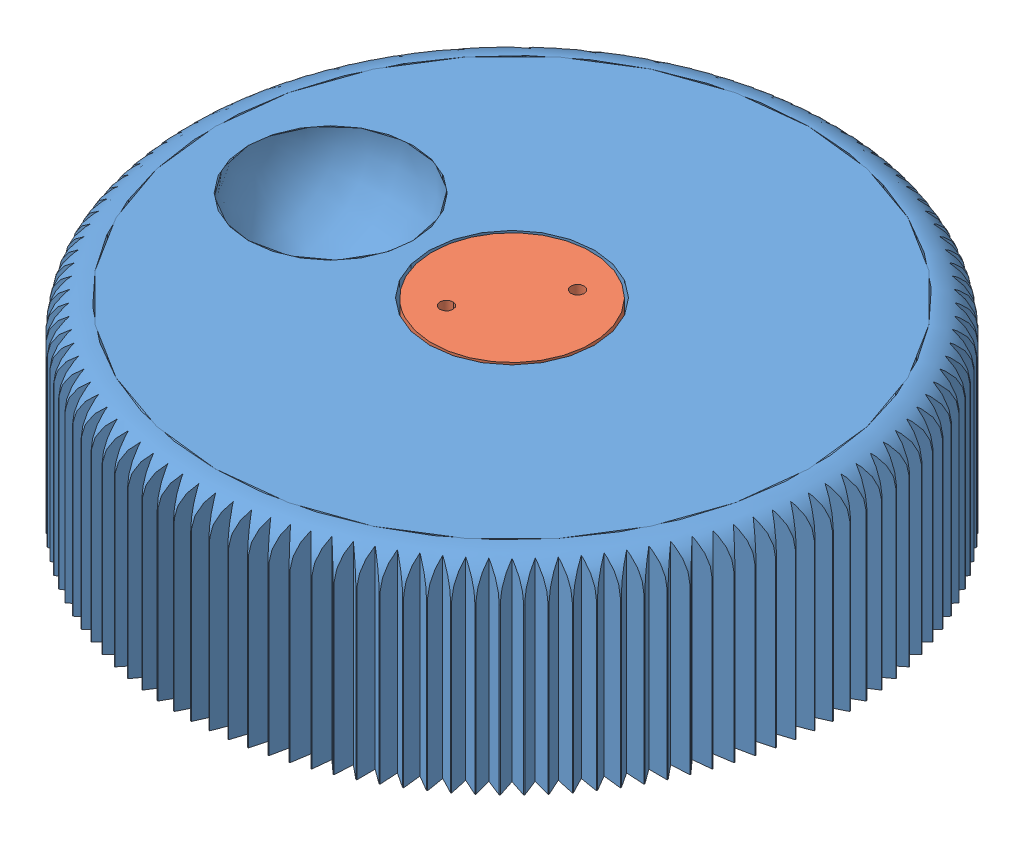
SolidWorks assembly shuttle_knob_construct, configuration По умолчанию. Lengths in mm.
Overall size (40 19.5 40).
2 component instances, 2 part files, 2 mates.
Components (placement in the parent):
- shuttle_knob-1: shuttle_knob [По умолчанию] at origin size (40.28 19.5 40.28)
- shuttle_knob_cap-1: shuttle_knob_cap [По умолчанию] at (0 19.5 0) x (-0.837169 0 -0.546944) z (-0.546944 0 0.837169) size (9.85 6.08 9.85)
Mates (geometry in assembly coordinates):
- Совпадение2: coincident aligned: plane of shuttle_knob-1 through (0 19.5 0) normal (0 1 0); plane of shuttle_knob_cap-1 through (0 19.5 0) normal (0 1 0)
- Концентричный1: concentric anti-aligned: circle of shuttle_knob-1; circle of shuttle_knob_cap-1
